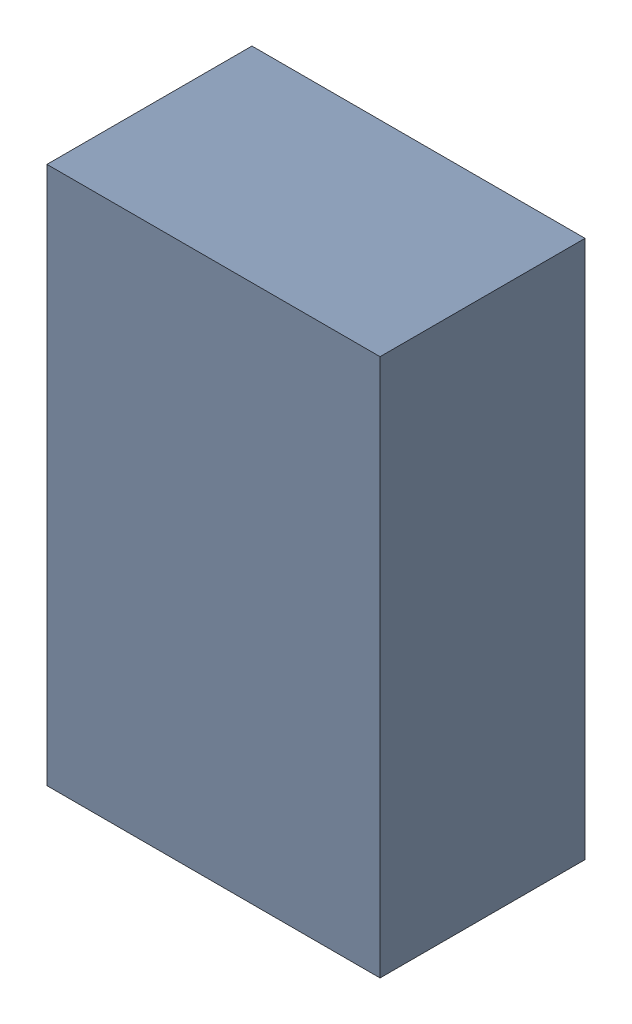
SolidWorks assembly Q83.step, configuration Default. Lengths in mm.
Overall size (0.65 1.05 0.4).
5 component instances, 3 part files, 0 mates.
Components (placement in the parent):
- 6297726448.step-1: 6297726448.step [Default] at (35.8394 -16.7132 0) x (0 1 0) z (0 0 1) size (1.05 0.65 0.4)
  - Body (10).step-1: Body (10).step [Default] at (-0.525 -0.325 0) size (1.05 0.65 0.4)
  - bigPin.step-1: bigPin.step [Default] at (0.175 -0.275 -0.0033) size (0.3 0.55 0.01)
  - smallPine.step-1: smallPine.step [Default] at (-0.475 -0.275 -0.0033) size (0.3 0.2 0.01)
  - smallPine.step-2: smallPine.step [Default] at (-0.475 0.075 -0.0033) size (0.3 0.2 0.01)
